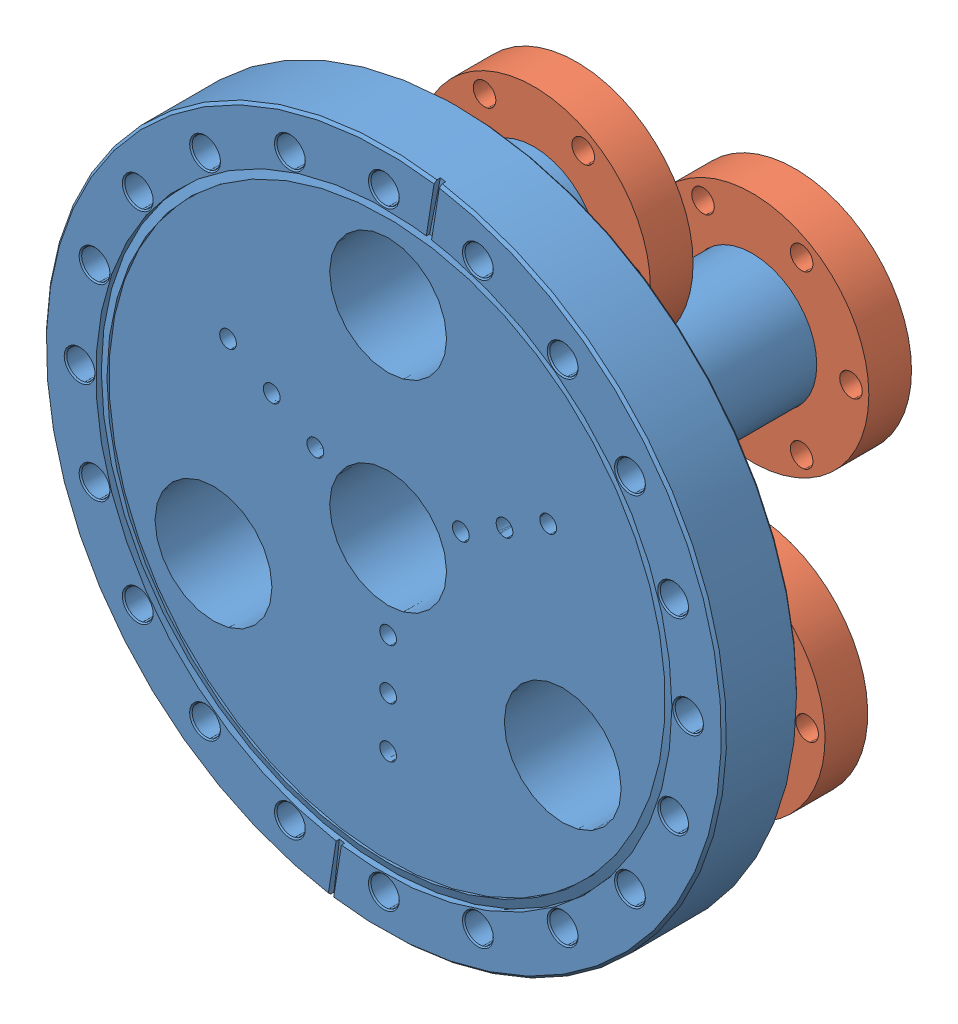
SolidWorks assembly custom_flange_8in, configuration Default. Lengths in mm.
Overall size (202.44 202.44 122.35).
5 component instances, 2 part files, 7 mates.
Components (placement in the parent):
- 110030_custom-1: 110030_custom [Default] at origin size (202.44 202.44 117.04)
- 110014 (2.75 X 1.5 NR)-1: 110014 (2.75 X 1.5 NR) [Default] at (0 0 -116.002) x (0 0 -1) z (1 0 0) size (12.7 69.34 69.34)
- 110014 (2.75 X 1.5 NR)-5: 110014 (2.75 X 1.5 NR) [Default] at (0 60 -51.002) x (0 0 -1) z (1 0 0) size (12.7 69.34 69.34)
- 110014 (2.75 X 1.5 NR)-6: 110014 (2.75 X 1.5 NR) [Default] at (-51.9615 -30 -51.002) x (0 0 -1) z (-0.5 0.866025 0) size (12.7 69.34 69.34)
- 110014 (2.75 X 1.5 NR)-7: 110014 (2.75 X 1.5 NR) [Default] at (51.9615 -30 -51.002) x (0 0 -1) z (-0.5 -0.866025 0) size (12.7 69.34 69.34)
Mates (geometry in assembly coordinates):
- Coincident1: coincident aligned: plane of 110030_custom-1 through (0 0 0) normal (0 0 1); plane of assembly through (0 0 0) normal (0 0 1)
- Coincident2: coincident aligned: plane of 110030_custom-1 through (0 0 0) normal (0 1 0); plane of assembly through (0 0 0) normal (0 1 0)
- Coincident3: coincident aligned: plane of 110030_custom-1 through (0 0 0) normal (1 0 0); plane of assembly through (0 0 0) normal (1 0 0)
- Concentric1: concentric aligned: cylinder of 110030_custom-1 through (0 0 -170.9249) axis (0 0 1) radius 19.05; cylinder of 110014 (2.75 X 1.5 NR)-1 through (0 0 -113.3477) axis (0 0 1) radius 19.177
- Distance1: distance = 100 mm aligned: plane of 110014 (2.75 X 1.5 NR)-1 through (0 -29.4105 -122.352) normal (0 0 -1); plane of 110030_custom-1 through (0 0 -22.352) normal (0 0 -1)
- Concentric2: concentric aligned: cylinder of 110030_custom-1 through (0 60 -105.9249) axis (0 0 1) radius 19.05; cylinder of 110014 (2.75 X 1.5 NR)-5 through (0 60 -48.3477) axis (0 0 1) radius 19.177
- Distance2: distance = 35 mm aligned: plane of 110014 (2.75 X 1.5 NR)-5 through (0 30.5895 -57.352) normal (0 0 -1); plane of 110030_custom-1 through (0 0 -22.352) normal (0 0 -1)
